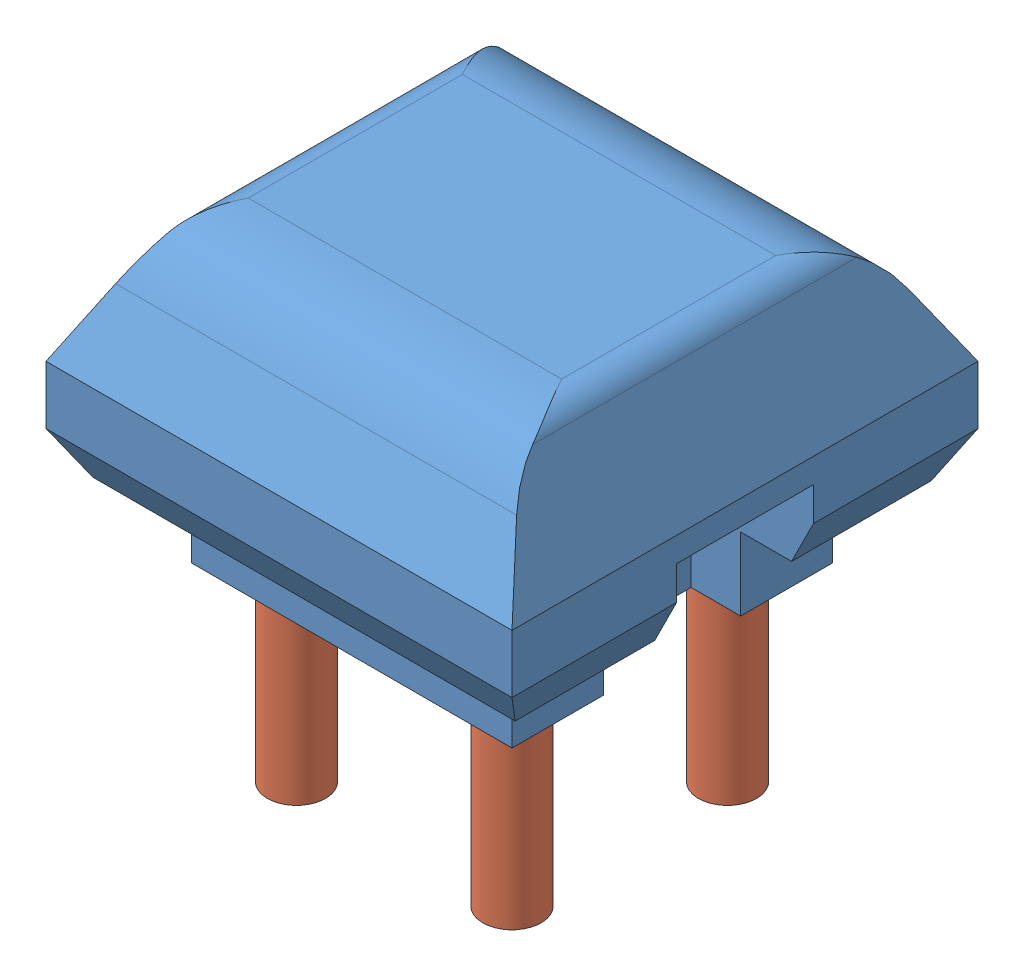
SolidWorks assembly Assem1, configuration Default. Lengths in mm.
Overall size (160 165 160).
5 component instances, 2 part files, 4 mates.
Components (placement in the parent):
- Electronics_GPS-1: Electronics_GPS [Default] at (45.0778 103.759 123.5701) size (160 100 160)
- GPS_Spacer-1: GPS_Spacer [Default] at (82.0778 -21.241 160.5701) x (-0.327705 0 -0.94478) z (0 1 0) size (20 20 65)
- GPS_Spacer-2: GPS_Spacer [Default] at (8.0778 -21.241 86.5701) x (0.991067 0 0.133362) z (0 1 0) size (20 20 65)
- GPS_Spacer-3: GPS_Spacer [Default] at (8.0778 -21.241 160.5701) x (0.953346 0 0.301881) z (0 1 0) size (20 20 65)
- GPS_Spacer-4: GPS_Spacer [Default] at (82.0778 -21.241 86.5701) x (0.550145 0 -0.835069) z (0 1 0) size (20 20 65)
Mates (geometry in assembly coordinates):
- Coincident1: coincident: circle of assembly; circle of assembly; circle of Electronics_GPS-1; circle of GPS_Spacer-1
- Coincident2: coincident: circle of assembly; circle of assembly; circle of Electronics_GPS-1; circle of GPS_Spacer-3
- Coincident3: coincident: circle of assembly; circle of assembly; circle of Electronics_GPS-1; circle of GPS_Spacer-2
- Coincident4: coincident: circle of assembly; circle of assembly; circle of Electronics_GPS-1; circle of GPS_Spacer-4
